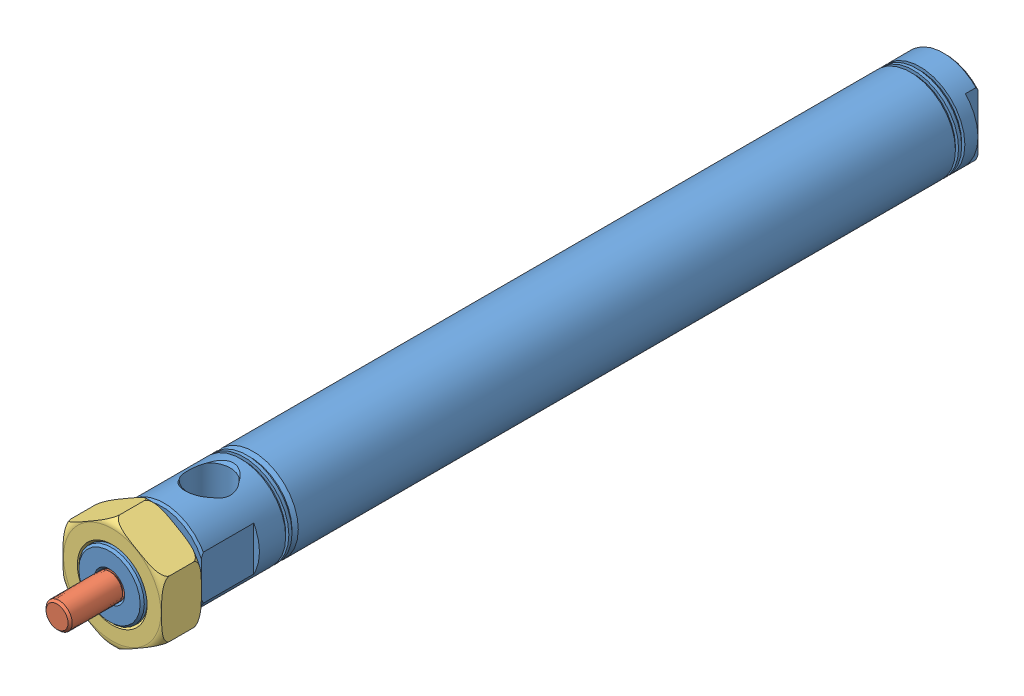
SolidWorks assembly Pneumatic Cylinder, configuration NCDMB075-0500C. Lengths in mm.
Overall size (24.93 28.62 215.14).
3 component instances, 3 part files, 8 mates.
Components (placement in the parent):
- Pneumatic Cylinder_Body-1: Pneumatic Cylinder_Body [075B] at origin size (21.84 21.84 202.44)
- Pneumatic Cylinder_Rod-1: Pneumatic Cylinder_Rod [075] at (0 0 -63.5) x (-1 0 0) z (0 0 1) size (19.05 19.05 186.27)
- Pneumatic Cylinder_Nut-1: Pneumatic Cylinder_Nut [075] at (0 0 102.077) x (-1 0 0) z (0 0 1) size (24.93 28.62 10.69)
Mates (geometry in assembly coordinates):
- Coincident1: coincident anti-aligned: plane of Pneumatic Cylinder_Body-1 through (0 0 -66) normal (0 0 1); plane of Pneumatic Cylinder_Rod-1 through (0 0 -66) normal (0 0 -1)
- Concentric1: concentric aligned: cylinder of Pneumatic Cylinder_Body-1 through (0 0 125.7611) axis (0 0 -1) radius 10.922; cylinder of Pneumatic Cylinder_Rod-1 through (0 0 -61) axis (0 0 -1) radius 9.525
- Parallel1: parallel anti-aligned: plane of Pneumatic Cylinder_Body-1 through (0 0 0) normal (1 0 0); plane of Pneumatic Cylinder_Rod-1
- Concentric3: concentric aligned: cylinder of Pneumatic Cylinder_Body-1 through (0 0 0) axis (0 0 -1) radius 7.9375; cylinder of Pneumatic Cylinder_Nut-1 through (0 0 106.903) axis (0 0 -1) radius 7.9375
- Coincident20: coincident anti-aligned: plane of Pneumatic Cylinder_Body-1 through (0 0 0) normal (1 0 0); plane of Pneumatic Cylinder_Nut-1
- Distance1: distance = 5.492 mm aligned: plane of Pneumatic Cylinder_Body-1 through (0 7.9375 107.569) normal (0 0 1); plane of Pneumatic Cylinder_Nut-1 through (0 0 102.077) normal (0 0 1)
- Coincident18: coincident anti-aligned: plane of Pneumatic Cylinder_Nut-1; plane of assembly through (0 0 0) normal (0 1 0)
- Coincident42: coincident anti-aligned: plane of Pneumatic Cylinder_Rod-1; plane of assembly through (0 0 0) normal (0 1 0)
